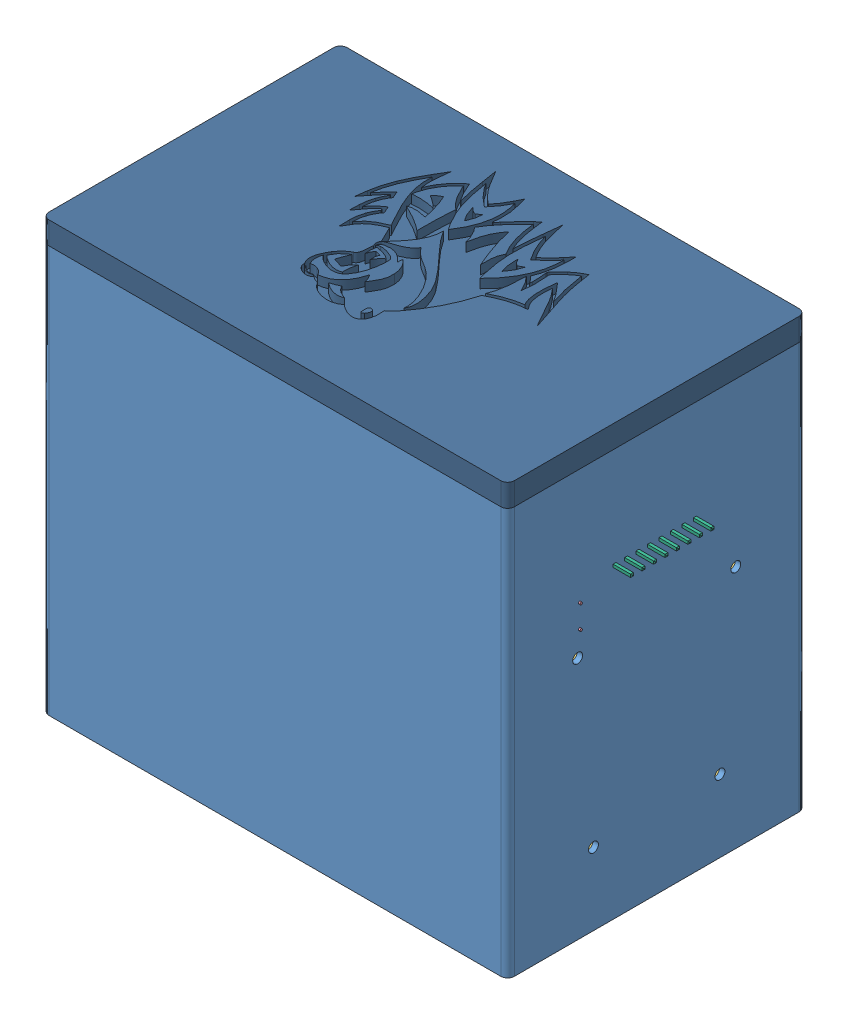
SolidWorks assembly rfid_assembly, configuration Default. Lengths in mm.
Overall size (108.4 95 68).
28 component instances, 10 part files, 9 mates.
Components (placement in the parent):
- rfid_bottom-1: rfid_bottom [Default] at (-113.405 42.4425 79.3574) size (103 90 66)
- ArduinoUno-1: ArduinoUno [Default] at (-108.406 49.0925 140.3515) x (-0.000425 0 1) z (-1 0 -0.000425) size (53.34 15.25 74.93)
- User Library-RFID-1: User Library-RFID [Default] at (47.845 81.6713 108.7014) x (0 0 1) z (-1 0 0) size (40 60 11.54)
  - User Library-RFID_Part1-1: User Library-RFID_Part1 [Default] at (-16.3439 30.7712 59.45) size (40 60 2)
  - User Library-RFID_Part10-1: User Library-RFID_Part10 [Default] at (20.709 20.1029 60.45) x (0 1 0) z (0 0 1) size (10.67 3.05 5.63)
  - User Library-RFID_User Library-S-PWSON-N12-1: User Library-RFID_User Library-S-PWSON-N12 [Default] at (4.1233 20.047 60.45) x (1 0 0) z (0 -1 0) size (3 0.8 3)
  - User Library-RFID_User Library-Header_Male_8Pin-1: User Library-RFID_User Library-Header_Male_8Pin [Default] at (12.9823 28.5305 62.74) x (-1 0 0) z (0 0 -1) size (20.32 2.49 11.54)
  - User Library-RFID_User Library-SMD Ceramic Capacitors_0603 (1608)_CH-1: User Library-RFID_User Library-SMD Ceramic Capacitors_0603 (1608)_CH [Default] at (-3.9959 5.9247 60.9127) size (1.72 0.91 0.98)
  - User Library-RFID_User Library-SMD Ceramic Capacitors_0603 (1608)_CH-2: User Library-RFID_User Library-SMD Ceramic Capacitors_0603 (1608)_CH [Default] at (-1.0806 5.9034 60.9127) size (1.72 0.91 0.98)
  - User Library-RFID_User Library-SMD Ceramic Capacitors_0603 (1608)_CH-3: User Library-RFID_User Library-SMD Ceramic Capacitors_0603 (1608)_CH [Default] at (2.2282 5.9089 60.9127) size (1.72 0.91 0.98)
  - User Library-RFID_User Library-SMD Ceramic Capacitors_0603 (1608)_CH-4: User Library-RFID_User Library-SMD Ceramic Capacitors_0603 (1608)_CH [Default] at (5.214 5.921 60.9127) size (1.72 0.91 0.98)
  - User Library-RFID_User Library-SMD Ceramic Capacitors_0603 (1608)_CH-5: User Library-RFID_User Library-SMD Ceramic Capacitors_0603 (1608)_CH [Default] at (8.193 5.9188 60.9127) size (1.72 0.91 0.98)
  - User Library-RFID_User Library-SMD Ceramic Capacitors_0603 (1608)_CH-6: User Library-RFID_User Library-SMD Ceramic Capacitors_0603 (1608)_CH [Default] at (11.3855 5.9271 60.9127) size (1.72 0.91 0.98)
  - User Library-RFID_User Library-SMD Ceramic Capacitors_0603 (1608)_CH-7: User Library-RFID_User Library-SMD Ceramic Capacitors_0603 (1608)_CH [Default] at (16.3593 23.3789 60.9127) size (1.72 0.91 0.98)
  - User Library-RFID_User Library-SMD Ceramic Capacitors_0603 (1608)_CH-8: User Library-RFID_User Library-SMD Ceramic Capacitors_0603 (1608)_CH [Default] at (16.3593 21.3117 60.9127) size (1.72 0.91 0.98)
  - User Library-RFID_User Library-SMD Ceramic Capacitors_0603 (1608)_CH-9: User Library-RFID_User Library-SMD Ceramic Capacitors_0603 (1608)_CH [Default] at (13.4136 25.6528 60.9127) size (1.72 0.91 0.98)
  - User Library-RFID_User Library-SMD Ceramic Capacitors_0603 (1608)_CH-10: User Library-RFID_User Library-SMD Ceramic Capacitors_0603 (1608)_CH [Default] at (13.517 19.0895 60.9127) size (1.72 0.91 0.98)
  - User Library-RFID_Part8-1: User Library-RFID_Part8 [Default] at (13.517 23.4826 60.704) size (1.6 0.81 0.51)
  - User Library-RFID_Part8-2: User Library-RFID_Part8 [Default] at (13.517 21.3121 60.704) size (1.6 0.81 0.51)
  - User Library-RFID_User Library-SMD Ceramic Capacitors_0603 (1608)_CH-11: User Library-RFID_User Library-SMD Ceramic Capacitors_0603 (1608)_CH [Default] at (-5.0547 25.4542 60.9127) size (1.72 0.91 0.98)
  - User Library-RFID_User Library-SMD Ceramic Capacitors_0603 (1608)_CH-12: User Library-RFID_User Library-SMD Ceramic Capacitors_0603 (1608)_CH [Default] at (-5.0547 21.4355 60.9127) size (1.72 0.91 0.98)
  - User Library-RFID_User Library-SMD Ceramic Capacitors_0603 (1608)_CH-13: User Library-RFID_User Library-SMD Ceramic Capacitors_0603 (1608)_CH [Default] at (-5.0547 19.367 60.9127) size (1.72 0.91 0.98)
  - User Library-RFID_Part8-3: User Library-RFID_Part8 [Default] at (-5.0547 23.3861 60.704) size (1.6 0.81 0.51)
  - User Library-RFID_Part8-4: User Library-RFID_Part8 [Default] at (-10.0418 25.4159 60.704) size (1.6 0.81 0.51)
  - User Library-RFID_Part8-5: User Library-RFID_Part8 [Default] at (-10.0625 23.4569 60.704) size (1.6 0.81 0.51)
  - User Library-RFID_Part8-6: User Library-RFID_Part8 [Default] at (-10.0541 27.4204 60.704) size (1.6 0.81 0.51)
- RSI1602-00.stp-2: RSI1602-00.stp [Default] at (-61.845 104.3997 90.9574) x (-1 0 0) z (0 0 -1) size (80.01 36.01 10.64)
- rfid_top-1: rfid_top [Default] at (-113.405 137.4425 79.3574) size (103 11.8 66)
Mates (geometry in assembly coordinates):
- Concentric6: concentric aligned: circle of rfid_bottom-1; circle of arduino uno-1
- Coincident2: coincident anti-aligned: plane of rfid_bottom-1 through (-113.405 47.4425 79.3574) normal (0 1 0); plane of arduino uno-1 through (-108.406 47.4425 140.3515) normal (0 -1 0)
- Concentric14: concentric anti-aligned: circle of rfid_bottom-1; circle of User Library-RFID-1/User Library-RFID_Part1-1
- Coincident4: coincident anti-aligned: plane of rfid_bottom-1 through (-11.605 132.4425 79.3574) normal (-1 0 0); plane of User Library-RFID-1/User Library-RFID_Part1-1 through (-11.605 112.4425 92.3574) normal (1 0 0)
- Coincident17: coincident aligned: plane of rfid_bottom-1 through (-10.405 132.4425 79.3574) normal (1 0 0); plane of rfid_top-1 through (-10.405 132.4425 79.3574) normal (1 0 0)
- Coincident18: coincident aligned: plane of rfid_bottom-1 through (-113.405 132.4425 79.3574) normal (0 0 -1); plane of rfid_top-1 through (-113.405 132.4425 79.3574) normal (0 0 -1)
- Coincident19: coincident anti-aligned: plane of rfid_bottom-1 through (-113.405 132.4425 79.3574) normal (0 1 0); plane of rfid_top-1 through (-113.405 132.4425 79.3574) normal (0 -1 0)
- Coincident23: coincident anti-aligned: plane of rfid_bottom-1 through (-113.405 132.4425 84.3574) normal (0 0 1); plane of RSI1602-00.stp-2 through (-21.845 86.3997 84.3574) normal (0 0 -1)
- Parallel2: parallel aligned: plane of rfid_bottom-1 through (-113.405 132.4425 79.3574) normal (0 1 0); plane of RSI1602-00.stp-2 through (-96.695 116.3997 84.3574) normal (0 1 0)
